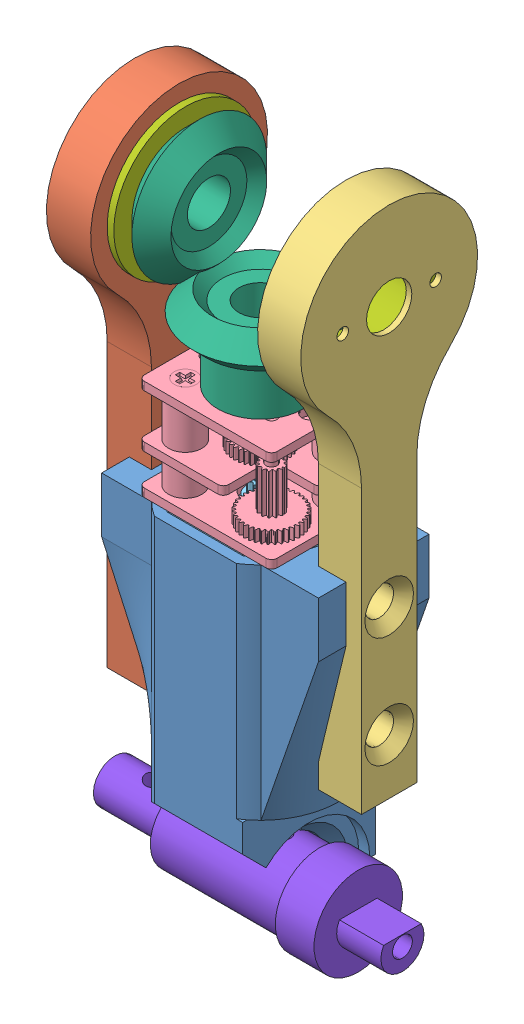
SolidWorks assembly motor module, configuration Default. Lengths in mm.
Overall size (26 62.12 17.23).
11 component instances, 8 part files, 17 mates.
Components (placement in the parent):
- motor mount v2-1: motor mount v2 [Default] at (6.722 6.9079 23.5345) size (19.6 28.5 12)
- outer gearside v2-1: outer gearside v2 [Default] at (-4.028 49.9079 23.5345) x (0 0 -1) z (0 -1 0) size (16 4 46.5)
- outer v2-1: outer v2 [Default] at (18.972 49.9079 23.5345) x (0 0 1) z (-1 0 0) size (16 46.5 3.9)
- MicroGearMotor v3 Higher Detail Gears No Lead Screw-1: MicroGearMotor v3 Higher Detail Gears No Lead Screw [Default] at (7.3343 28.9079 23.5345) size (12 26.96 10)
  - GearboxScaffolding-1: GearboxScaffolding [Default] at origin size (12 11.35 10)
  - DC Motor-1: DC Motor [Default] at origin size (12 18.75 10)
- rapid 50-8929-1: rapid 50-8929 [Default] at (7.3343 38.0179 23.5345) x (0.872999 0 0.487721) z (-0.487721 0 0.872999) size (12.2 7.5 12.2)
- rapid 50-8929-2: rapid 50-8929 [Default] at (-3.928 49.9079 23.5345) x (0 0.673583 -0.739112) z (0 -0.739112 -0.673583) size (12.2 7.5 12.2)
- bearing 8mm ID 12OD-1: bearing 8mm ID 12OD [Default] at (0.672 49.9079 23.5345) x (0 -0.381849 0.924225) z (0 -0.924225 -0.381849) size (13 3.3 13)
- bearing 8mm ID 12OD-2: bearing 8mm ID 12OD [Default] at (14.372 49.9079 23.5345) x (0 0.381849 -0.924225) z (0 -0.924225 -0.381849) size (13 3.3 13)
- axil-2: axil [Default] at (5.172 0.4079 23.5345) x (-1 0 0) z (0 1 0) size (26 8 8)
Mates (geometry in assembly coordinates):
- Concentric1: concentric anti-aligned: cylinder of motor mount v2-1 through (17.572 26.4079 23.5345) axis (1 0 0) radius 0.8; cylinder of outer gearside v2-1 through (-4.028 26.4079 23.5345) axis (-1 0 0) radius 1.3
- Concentric2: concentric anti-aligned: cylinder of motor mount v2-1 through (17.572 16.4079 23.5345) axis (1 0 0) radius 0.8; cylinder of outer gearside v2-1 through (-4.028 16.4079 23.5345) axis (-1 0 0) radius 1.3
- Coincident1: coincident anti-aligned: plane of motor mount v2-1 through (-0.028 0.4079 21.0345) normal (-1 0 0); plane of outer gearside v2-1 through (-0.028 36.9561 36.0345) normal (1 0 0)
- Concentric3: concentric aligned: cylinder of motor mount v2-1 through (17.572 26.4079 23.5345) axis (1 0 0) radius 0.8; cylinder of outer v2-1 through (18.972 26.4079 23.5345) axis (1 0 0) radius 1.3
- Concentric4: concentric aligned: cylinder of motor mount v2-1 through (17.572 16.4079 23.5345) axis (1 0 0) radius 0.8; cylinder of outer v2-1 through (18.972 16.4079 23.5345) axis (1 0 0) radius 1.3
- Coincident2: coincident anti-aligned: plane of motor mount v2-1 through (15.072 6.9079 23.5345) normal (1 0 0); plane of outer v2-1 through (15.072 36.9561 11.0345) normal (-1 0 0)
- Coincident3: coincident anti-aligned: plane of motor mount v2-1 through (6.722 28.9079 23.5345) normal (0 1 0); plane of MicroGearMotor v3 Higher Detail Gears No Lead Screw-1/GearboxScaffolding-1 through (7.3343 28.9079 23.5345) normal (0 -1 0)
- Concentric5: concentric anti-aligned: cylinder of motor mount v2-1 through (7.3343 9.9079 23.5345) axis (0 1 0) radius 6.2077; cylinder of MicroGearMotor v3 Higher Detail Gears No Lead Screw-1/DC Motor-1 through (7.3343 28.9079 23.5345) axis (0 -1 0) radius 6
- Parallel1: parallel aligned: plane of motor mount v2-1 through (0.822 8.9079 17.5345) normal (0 0 -1); plane of MicroGearMotor v3 Higher Detail Gears No Lead Screw-1/GearboxScaffolding-1 through (6.8343 28.9079 18.5345) normal (0 0 -1)
- Concentric6: concentric anti-aligned: cylinder of MicroGearMotor v3 Higher Detail Gears No Lead Screw-1/GearboxScaffolding-1 through (7.3343 38.0179 23.5345) axis (0 1 0) radius 1.7; cylinder of rapid 50-8929-1 through (7.3343 38.0179 23.5345) axis (0 -1 0) radius 3.85
- Concentric7: concentric aligned: cylinder of outer gearside v2-1 through (-0.028 49.9079 23.5345) axis (-1 0 0) radius 6; cylinder of bearing 8mm ID 12OD-1 through (-1.9627 49.9079 23.5345) axis (-1 0 0) radius 5.9
- Concentric8: concentric aligned: cylinder of outer v2-1 through (15.072 49.9079 23.5345) axis (1 0 0) radius 6; cylinder of bearing 8mm ID 12OD-2 through (17.0067 49.9079 23.5345) axis (1 0 0) radius 5.9
- Coincident6: coincident anti-aligned: plane of outer gearside v2-1 through (-0.028 36.9561 36.0345) normal (1 0 0); plane of bearing 8mm ID 12OD-1 through (-0.028 47.655 28.9874) normal (-1 0 0)
- Coincident7: coincident anti-aligned: plane of outer v2-1 through (15.072 36.9561 11.0345) normal (-1 0 0); plane of bearing 8mm ID 12OD-2 through (15.072 52.1608 18.0816) normal (1 0 0)
- Concentric9: concentric aligned: cylinder of rapid 50-8929-2 through (-3.928 49.9079 23.5345) axis (-1 0 0) radius 3.85; cylinder of bearing 8mm ID 12OD-1 through (-1.9627 49.9079 23.5345) axis (-1 0 0) radius 4.1
- Coincident8: coincident anti-aligned: plane of rapid 50-8929-2 through (0.572 53.1867 19.9367) normal (-1 0 0); plane of bearing 8mm ID 12OD-1 through (0.572 47.4259 29.5419) normal (1 0 0)
- Coincident9: coincident anti-aligned: plane of MicroGearMotor v3 Higher Detail Gears No Lead Screw-1/GearboxScaffolding-1 through (7.3343 38.0179 23.5345) normal (0 1 0); plane of rapid 50-8929-1 through (10.6954 38.0179 25.4122) normal (0 -1 0)
